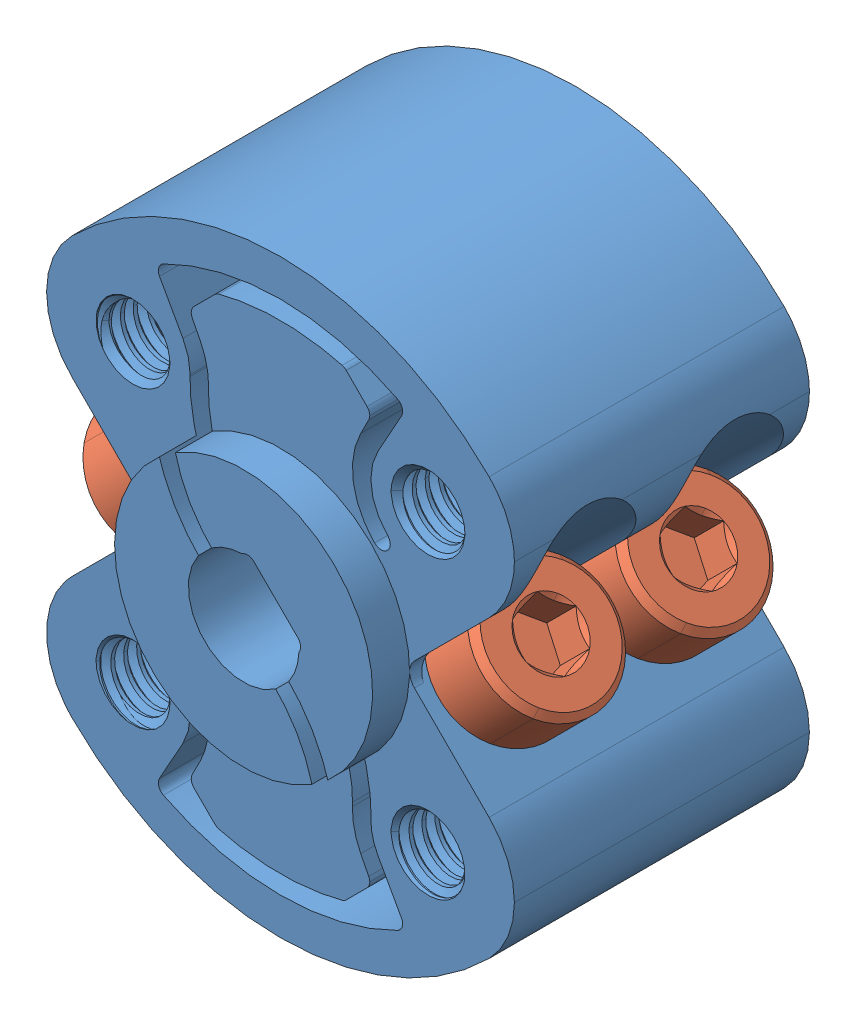
SolidWorks assembly 6mm D-bore, Double Length 1312-0016-1006, configuration Default. Lengths in mm.
Overall size (28.36 32 18.95).
5 component instances, 2 part files, 0 mates.
Components (placement in the parent):
- 1312-0016-1006.STEP-1: 1312-0016-1006.STEP [Default] at (-23.4637 -17.2124 31.7239) size (25.38 32 18)
- 2800-0004-0014_90128A207.STEP-1: 2800-0004-0014_90128A207.STEP [Default] at (-25.5166 -28.3312 27.7239) x (0.5 -0.5 0.707107) z (-0.707107 -0.707107 0) size (7 7 18.01)
- 2800-0004-0014_90128A207.STEP-2: 2800-0004-0014_90128A207.STEP [Default] at (-25.5166 -28.3312 19.7239) x (0.5 -0.5 0.707107) z (-0.707107 -0.707107 0) size (7 7 18.01)
- 2800-0004-0014_90128A207.STEP-3: 2800-0004-0014_90128A207.STEP [Default] at (-21.4109 -6.0937 27.7239) x (-0.5 0.5 0.707107) z (0.707107 0.707107 0) size (7 7 18.01)
- 2800-0004-0014_90128A207.STEP-4: 2800-0004-0014_90128A207.STEP [Default] at (-21.4109 -6.0937 19.7239) x (-0.5 0.5 0.707107) z (0.707107 0.707107 0) size (7 7 18.01)
